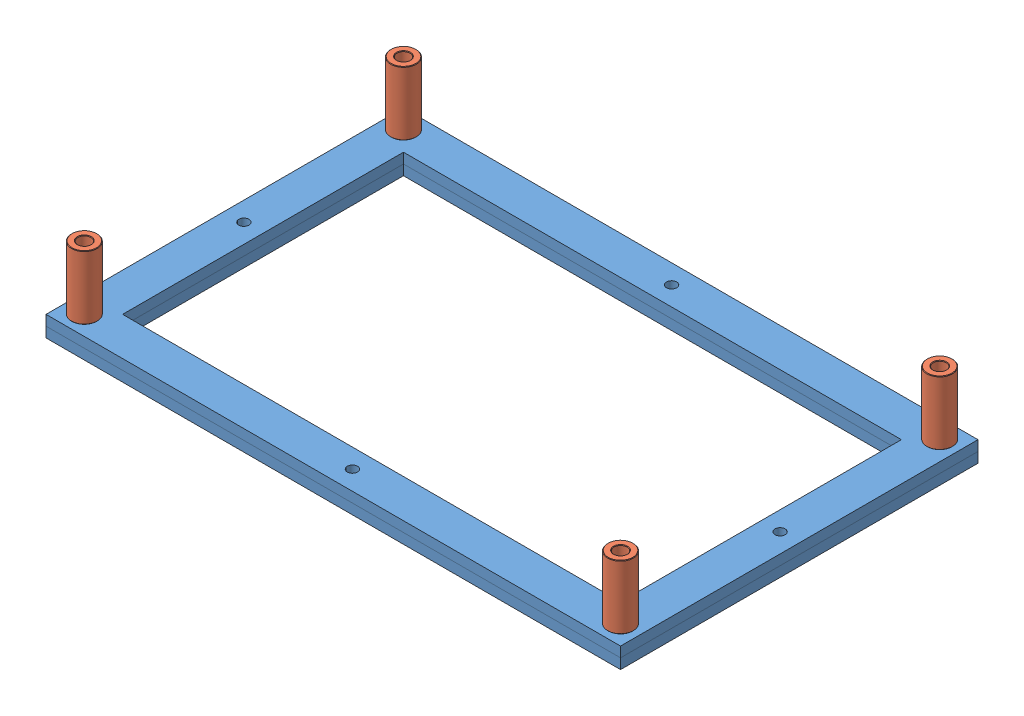
SolidWorks assembly m-cl_diffusor-film-assembly_v1.0, configuration Default. Lengths in mm.
Overall size (225 33 140).
6 component instances, 2 part files, 11 mates.
Components (placement in the parent):
- m-cl_diffusor-film-holder_v1.0-1: m-cl_diffusor-film-holder_v1.0 [Default] at origin size (225 4 140)
- m-cl_diffusor-film-holder_v1.0-2: m-cl_diffusor-film-holder_v1.0 [Default] at (0 -4 0) size (225 4 140)
- Aluminum Spacer 25mm-1: Aluminum Spacer 25mm [Default] at (-77.5 29 -62.5) x (0.837169 0 0.546944) z (0 -1 0) size (10 10 25)
- Aluminum Spacer 25mm-2: Aluminum Spacer 25mm [Default] at (132.5 4 62.5) x (-0.837169 0 -0.546944) z (0 1 0) size (10 10 25)
- Aluminum Spacer 25mm-3: Aluminum Spacer 25mm [Default] at (132.5 4 -62.5) x (-0.837169 0 -0.546944) z (0 1 0) size (10 10 25)
- Aluminum Spacer 25mm-4: Aluminum Spacer 25mm [Default] at (-77.5 4 62.5) x (-0.837169 0 -0.546944) z (0 1 0) size (10 10 25)
Mates (geometry in assembly coordinates):
- Coincident1: coincident: plane of assembly; plane of assembly; plane of m-cl_diffusor-film-holder_v1.0-1 through (-85 4 70) normal (0 0 1); plane of m-cl_diffusor-film-holder_v1.0-2 through (-85 0 70) normal (0 0 1)
- Coincident2: coincident: plane of assembly; plane of assembly; plane of m-cl_diffusor-film-holder_v1.0-1 through (-85 4 70) normal (-1 0 0); plane of m-cl_diffusor-film-holder_v1.0-2 through (-85 0 70) normal (-1 0 0)
- Coincident3: coincident: plane of assembly; plane of assembly; plane of m-cl_diffusor-film-holder_v1.0-1 through (0 0 0) normal (0 -1 0); plane of m-cl_diffusor-film-holder_v1.0-2 through (0 0 0) normal (0 1 0)
- Coincident5: coincident: plane of assembly; plane of assembly; plane of Aluminum Spacer 25mm-3 through (132.5 4 -62.5) normal (0 -1 0); plane of Aluminum Spacer 25mm-4 through (-77.5 4 62.5) normal (0 -1 0)
- Coincident6: coincident: plane of assembly; plane of assembly; plane of Aluminum Spacer 25mm-1 through (-77.5 4 -62.5) normal (0 -1 0); plane of Aluminum Spacer 25mm-4 through (-77.5 4 62.5) normal (0 -1 0)
- Coincident7: coincident: plane of assembly; plane of assembly; plane of Aluminum Spacer 25mm-1 through (-77.5 4 -62.5) normal (0 -1 0); plane of Aluminum Spacer 25mm-2 through (132.5 4 62.5) normal (0 -1 0)
- Coincident8: coincident: plane of assembly; plane of assembly; plane of m-cl_diffusor-film-holder_v1.0-1 through (0 4 0) normal (0 1 0); plane of Aluminum Spacer 25mm-3 through (132.5 4 -62.5) normal (0 -1 0)
- Concentric1: concentric: cylinder of assembly; cylinder of assembly; cylinder of m-cl_diffusor-film-holder_v1.0-1 through (132.5 4 -62.5) axis (0 -1 0) radius 2; cylinder of Aluminum Spacer 25mm-3 through (132.5 29 -62.5) axis (0 -1 0) radius 2.55
- Concentric2: concentric: cylinder of assembly; cylinder of assembly; cylinder of m-cl_diffusor-film-holder_v1.0-1 through (132.5 4 62.5) axis (0 -1 0) radius 2; cylinder of Aluminum Spacer 25mm-2 through (132.5 29 62.5) axis (0 -1 0) radius 2.55
- Concentric3: concentric: cylinder of assembly; cylinder of assembly; cylinder of m-cl_diffusor-film-holder_v1.0-1 through (-77.5 4 -62.5) axis (0 -1 0) radius 2; cylinder of Aluminum Spacer 25mm-1 through (-77.5 4 -62.5) axis (0 1 0) radius 2.55
- Concentric4: concentric: cylinder of assembly; cylinder of assembly; cylinder of m-cl_diffusor-film-holder_v1.0-1 through (-77.5 4 62.5) axis (0 -1 0) radius 2; cylinder of Aluminum Spacer 25mm-4 through (-77.5 29 62.5) axis (0 -1 0) radius 2.55
